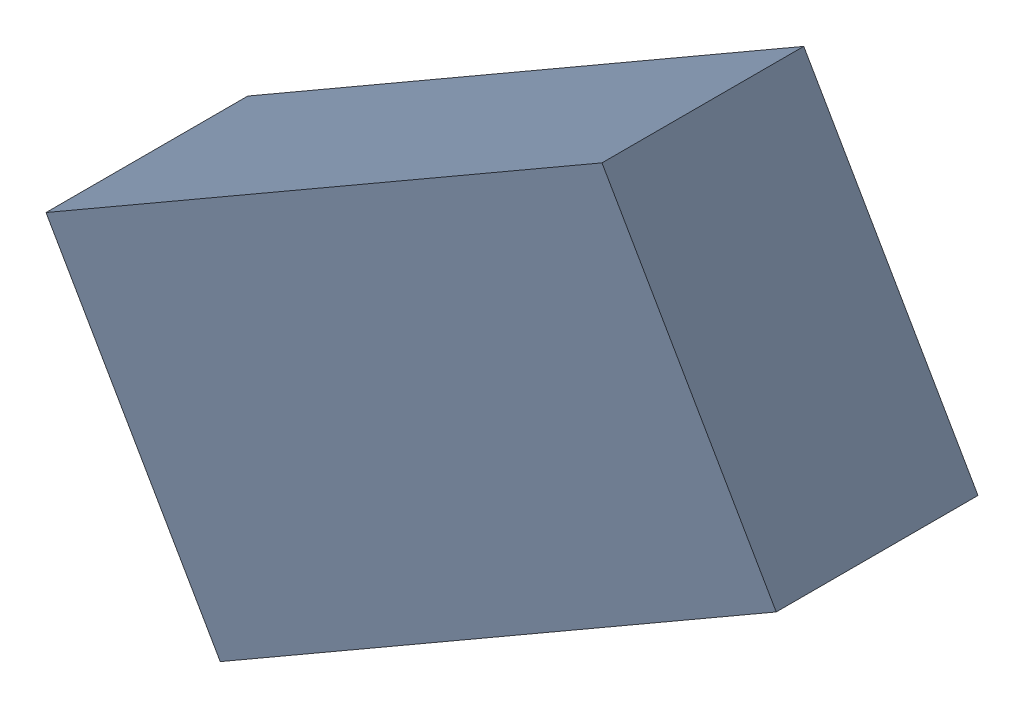
SolidWorks assembly L2_TDA5, configuration Standard. Lengths in mm.
Overall size (1.99 1.7 0.55).
2 component instances, 1 part files, 0 mates.
Components (placement in the parent):
- 885543736-1: 885543736 [Standard] at (-51.462 -30.5011 0) size (1.99 1.7 0.55)
  - Extruded_21-1: Extruded_21 [Standard] at origin size (1.99 1.7 0.55)
